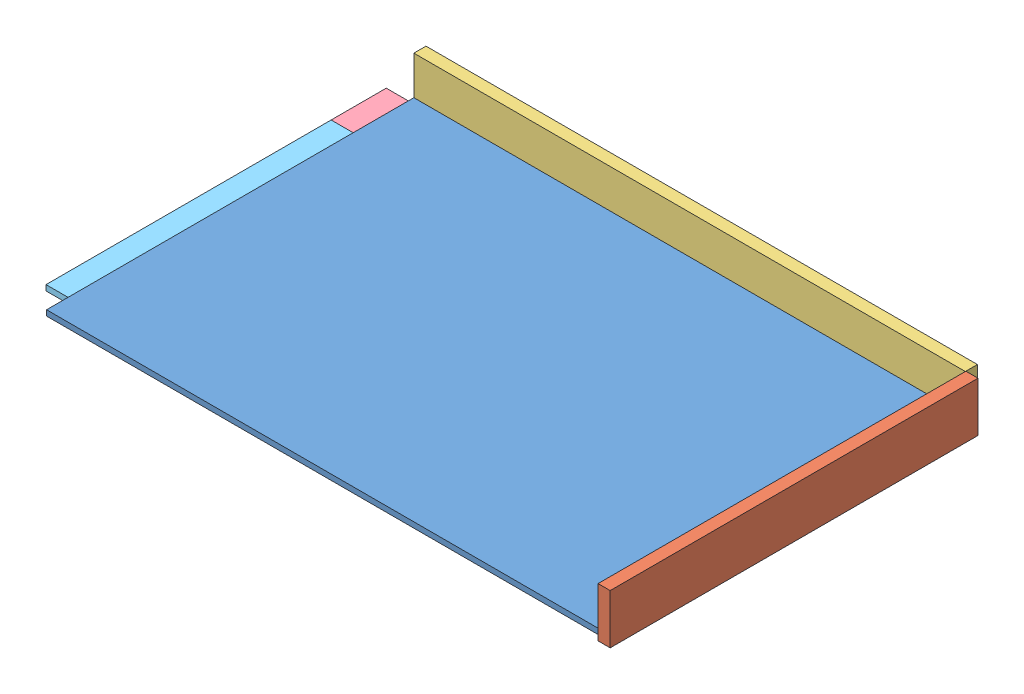
SolidWorks assembly Assemblage2, configuration Default. Lengths in mm.
Overall size (1072 90 688).
6 component instances, 5 part files, 15 mates.
Components (placement in the parent):
- planche_1000x666x10-1: planche_1000x666x10 [Default] at (-679.6071 67.2585 378.6849) size (1000 10 666)
- planche_667x90x22-1: planche_667x90x22 [Default] at (342.3929 57.2585 -288.3151) x (0 0 1) z (-1 0 0) size (667 90 22)
- planche_1000x90x22-1: planche_1000x90x22 [Default] at (-679.6071 57.2585 -309.3151) size (1000 90 22)
- planche_1050x100x10-1: planche_1050x100x10 [Default] at (-729.6071 57.2585 -187.3151) size (1050 10 100)
- planche_517x100x10-1: planche_517x100x10 [Default] at (220.3929 57.2585 -187.3151) x (0 0 1) z (-1 0 0) size (517 10 100)
- planche_517x100x10-2: planche_517x100x10 [Default] at (-729.6071 57.2585 -187.3151) x (0 0 1) z (-1 0 0) size (517 10 100)
Mates (geometry in assembly coordinates):
- Coïncidente1: coincident anti-aligned: plane of planche_1000x666x10-1 through (320.3929 77.2585 378.6849) normal (1 0 0); plane of planche_667x90x22-1 through (320.3929 147.2585 -288.3151) normal (-1 0 0)
- Coïncidente2: coincident aligned: plane of planche_1000x666x10-1 through (-679.6071 77.2585 378.6849) normal (0 0 1); plane of planche_667x90x22-1 through (320.3929 57.2585 378.6849) normal (0 0 1)
- Coïncidente3: coincident anti-aligned: plane of planche_1000x666x10-1 through (-679.6071 77.2585 -287.3151) normal (0 0 -1); plane of planche_1000x90x22-1 through (-679.6071 147.2585 -287.3151) normal (0 0 1)
- Coïncidente4: coincident aligned: plane of planche_1000x666x10-1 through (-679.6071 77.2585 378.6849) normal (-1 0 0); plane of planche_1000x90x22-1 through (-679.6071 57.2585 -287.3151) normal (-1 0 0)
- Coïncidente5: coincident anti-aligned: plane of planche_1000x666x10-1 through (-679.6071 67.2585 -287.3151) normal (0 -1 0); plane of planche_1050x100x10-1 through (-729.6071 67.2585 -287.3151) normal (0 1 0)
- Coïncidente6: coincident anti-aligned: plane of planche_1000x90x22-1 through (-679.6071 147.2585 -287.3151) normal (0 0 1); plane of planche_1050x100x10-1 through (-729.6071 67.2585 -287.3151) normal (0 0 -1)
- Coïncidente7: coincident aligned: plane of planche_1000x90x22-1 through (-679.6071 57.2585 -287.3151) normal (0 -1 0); plane of planche_1050x100x10-1 through (-729.6071 57.2585 -287.3151) normal (0 -1 0)
- Coïncidente8: coincident anti-aligned: plane of planche_667x90x22-1 through (320.3929 147.2585 -288.3151) normal (-1 0 0); plane of planche_1050x100x10-1 through (320.3929 67.2585 -187.3151) normal (1 0 0)
- Coïncidente9: coincident aligned: plane of planche_667x90x22-1 through (320.3929 57.2585 -288.3151) normal (0 -1 0); plane of planche_1050x100x10-1 through (-729.6071 57.2585 -287.3151) normal (0 -1 0)
- Coïncidente10: coincident anti-aligned: plane of planche_1000x666x10-1 through (-679.6071 67.2585 -287.3151) normal (0 -1 0); plane of planche_517x100x10-1 through (320.3929 67.2585 -187.3151) normal (0 1 0)
- Coïncidente11: coincident anti-aligned: plane of planche_1050x100x10-1 through (-729.6071 67.2585 -187.3151) normal (0 0 1); plane of planche_517x100x10-1 through (220.3929 67.2585 -187.3151) normal (0 0 -1)
- Coïncidente12: coincident anti-aligned: plane of planche_667x90x22-1 through (320.3929 147.2585 -288.3151) normal (-1 0 0); plane of planche_517x100x10-1 through (320.3929 67.2585 -187.3151) normal (1 0 0)
- Coïncidente13: coincident anti-aligned: plane of planche_1000x666x10-1 through (-679.6071 67.2585 -287.3151) normal (0 -1 0); plane of ? through (-629.6071 67.2585 -171.006) normal (0 1 0)
- Coïncidente14: coincident aligned: plane of planche_1050x100x10-1 through (-729.6071 67.2585 -187.3151) normal (-1 0 0); plane of ? through (-729.6071 67.2585 -171.006) normal (-1 0 0)
- Coïncidente15: coincident anti-aligned: plane of planche_1050x100x10-1 through (-729.6071 67.2585 -187.3151) normal (0 0 1); plane of ? through (-729.6071 67.2585 -171.006) normal (0 0 -1)
